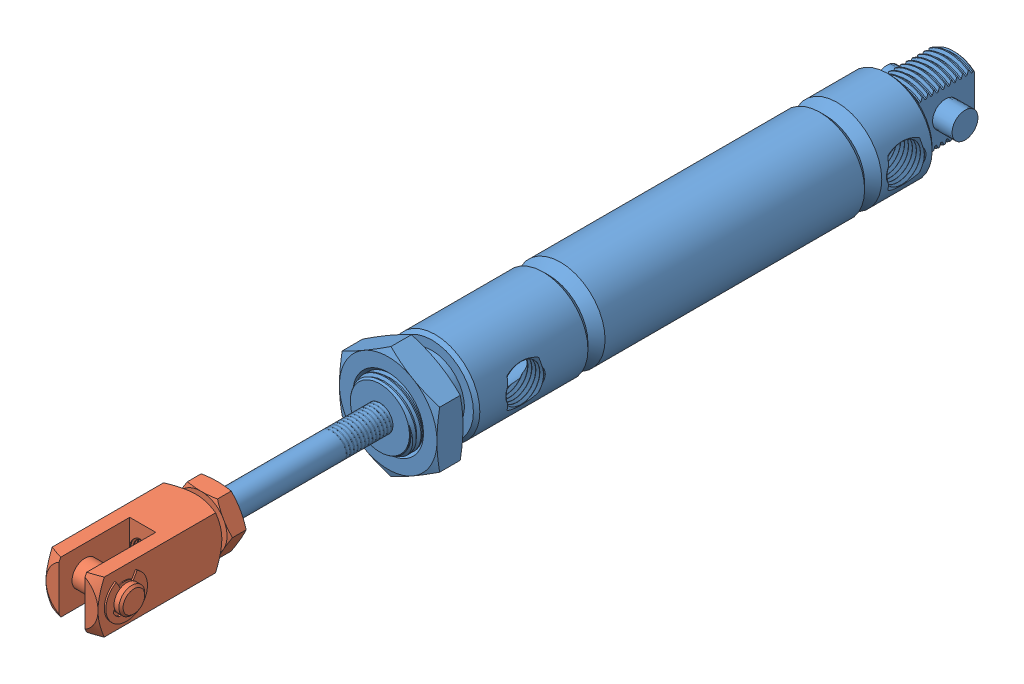
SolidWorks assembly 1.5in .75 bore piston, configuration Default. Lengths in mm.
Overall size (23.81 27.5 215.71).
2 component instances, 2 part files, 3 mates.
Components (placement in the parent):
- 6498K633-1: 6498K633 [6498K633] at (-10.6785 118.4903 177.639) size (23.81 27.5 191.42)
- .75 bore Clevis-1: .75 bore Clevis [6498K42] at (-10.6785 118.4903 286.478) x (1 0 0) z (0 -1 0) size (20.16 35.74 12.7)
Mates (geometry in assembly coordinates):
- LimitDistance1: limit distance = 39.624 mm anti-aligned: plane of .75 bore Clevis-1 through (-10.6785 105.7903 281.144) normal (0 0 -1); plane of 6498K633-1 through (-10.6785 118.4903 241.52) normal (0 0 1)
- Concentric1: concentric anti-aligned: cylinder of 6498K633-1 through (-10.6785 118.4903 177.131) axis (0 0 -1) radius 3.175; circle of .75 bore Clevis-1
- Parallel1: parallel aligned: plane of 6498K633-1 through (-5.916 126.4278 148.007) normal (1 0 0); plane of .75 bore Clevis-1 through (-4.3285 112.1403 286.478) normal (1 0 0)
